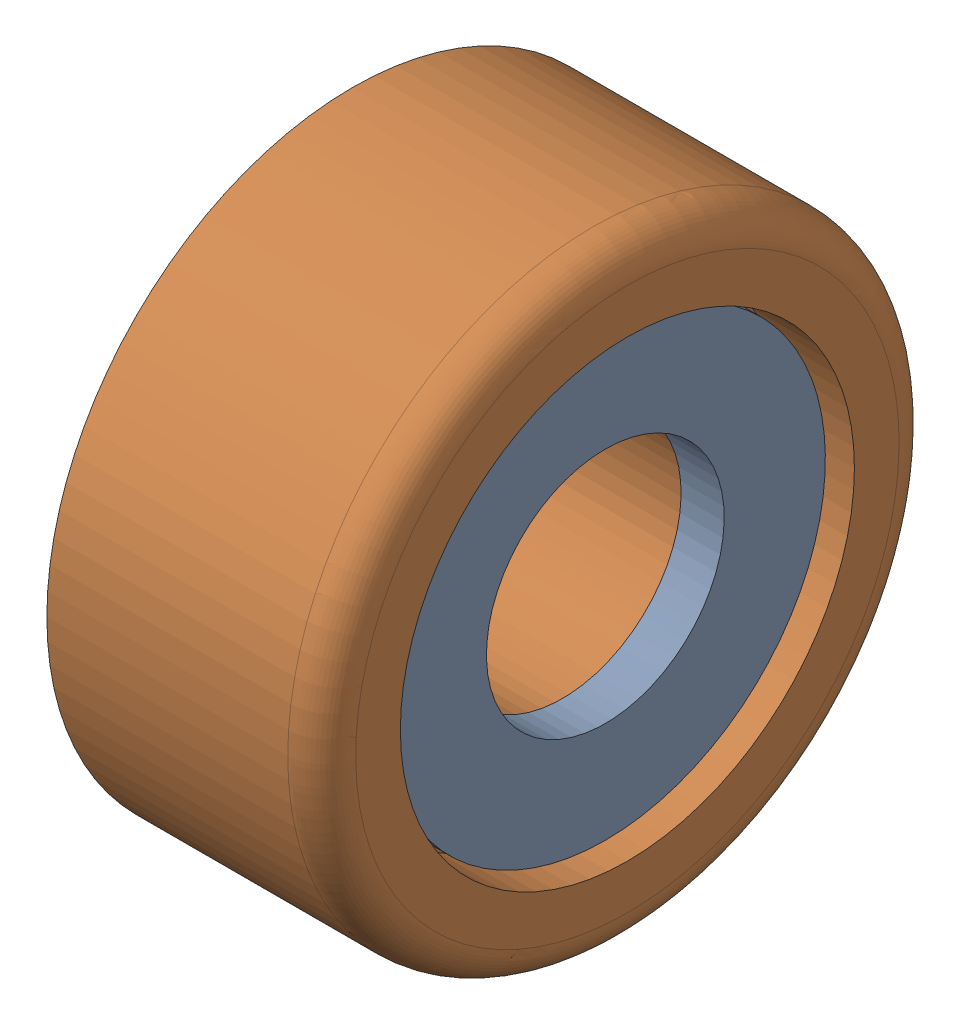
SolidWorks assembly 3,5 mm (Video Yellow), configuration Default. Lengths in mm.
Overall size (4.05 9 9).
2 component instances, 2 part files, 0 mates.
Components (placement in the parent):
- Part216_2-1: Part216_2 [Default] at (32.1699 -0.8638 41.0298) x (0 1 0) z (1 0 0) size (6.48 6.48 0.63)
- Part215_2-1: Part215_2 [Default] at (29.0831 -0.8638 41.0298) x (0 1 0) z (1 0 0) size (9 9 4.05)
